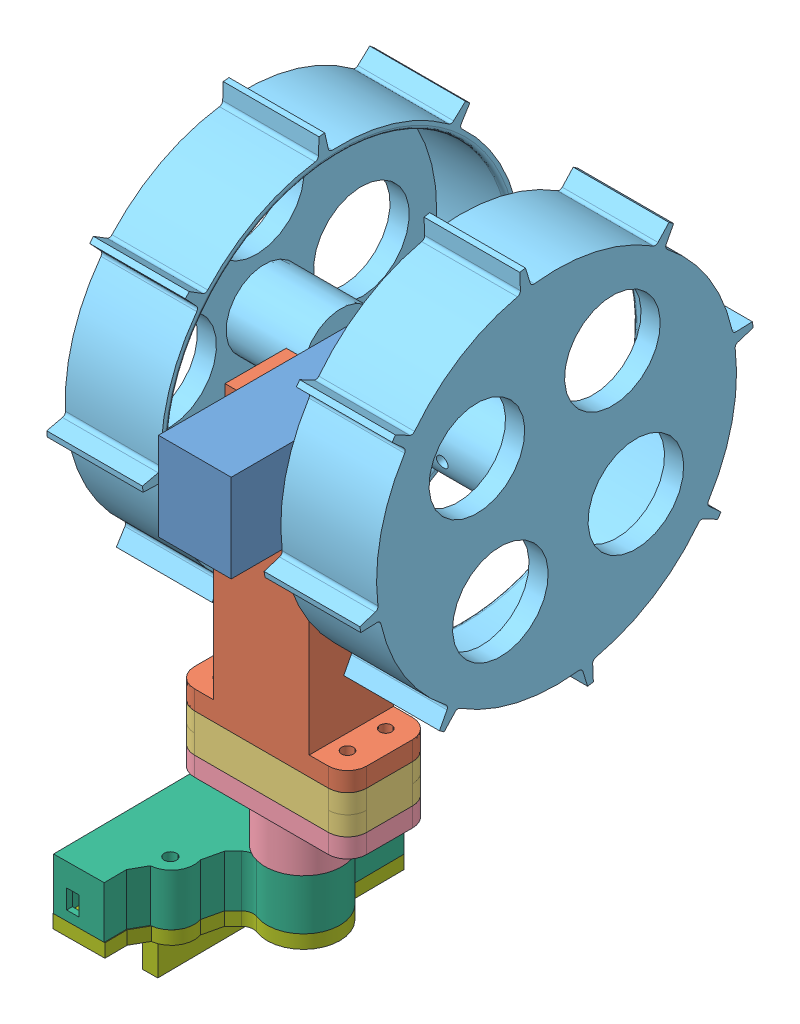
SolidWorks assembly Ensamblaje1, configuration Predeterminado. Lengths in mm.
Overall size (81.29 201.76 146.4).
8 component instances, 7 part files, 16 mates.
Components (placement in the parent):
- motor-1: motor [Predeterminado] at (-10.4339 -8.2966 65) size (39 23 65)
- soporte motor-1: soporte motor [Predeterminado] at (-10.4339 -43.2966 69.1262) x (-1 0 0) z (0 0 1) size (45 75 22)
- separador 2-1: separador 2 [Predeterminado] at (-10.4339 -77.2966 69.1262) size (45 10 22)
- separador v2-1: separador v2 [Predeterminado] at (-10.4339 -87.2966 69.1262) size (45 17 22)
- rueda v2.1-1: rueda v2.1 [Predeterminado] at (30.0214 3.2034 43.5) x (0 -0.985359 -0.170493) z (-1 0 0) size (104 104 25)
- rueda v2.1-2: rueda v2.1 [Predeterminado] at (-51.2707 3.2034 43.5) x (0 -0.771721 0.635961) z (1 0 0) size (104 104 25)
- base 1.b-1: base 1.b [SimetríaPredeterminado] at (-27.9332 -87.2966 69.2777) x (-0.008654 0 -0.999963) z (-0.999963 0 0.008654) size (63.25 13.5 40.3)
- tapa1.a-1: tapa1.a [SimetríaPredeterminado] at (-27.9332 -87.2966 69.2777) x (-0.008654 0 -0.999963) z (-0.999963 0 0.008654) size (63.34 24.56 40.5)
Mates (geometry in assembly coordinates):
- Coincidente1: coincident anti-aligned: plane of motor-1 through (-19.9339 14.7034 32.5) normal (-1 0 0); plane of soporte motor-1 through (-19.9339 -55.2966 77.1262) normal (1 0 0)
- Coincidente3: coincident anti-aligned: plane of motor-1 through (-10.4339 -8.2966 65) normal (0 -1 0); plane of soporte motor-1 through (-0.9339 -8.2966 10.1262) normal (0 1 0)
- Concéntrica2: concentric anti-aligned: cylinder of soporte motor-1 through (6.0661 -100.2966 64.1262) axis (0 1 0) radius 1.55; cylinder of separador 2-1 through (6.0661 -20.2966 64.1262) axis (0 -1 0) radius 1.55
- Coincidente4: coincident aligned: cylinder of separador 2-1 through (6.0661 -20.2966 64.1262) axis (0 -1 0) radius 1.55; circle of separador v2-1
- Concéntrica3: concentric aligned: cylinder of separador 2-1 through (6.0661 -20.2966 64.1262) axis (0 -1 0) radius 1.55; cylinder of separador v2-1 through (6.0661 -30.2966 64.1262) axis (0 -1 0) radius 1.55
- Coincidente5: coincident anti-aligned: plane of separador 2-1 through (-10.4339 -70.2966 69.1262) normal (0 -1 0); plane of separador v2-1 through (-10.4339 -70.2966 69.1262) normal (0 1 0)
- Concéntrica4: concentric anti-aligned: cylinder of motor-1 through (9.0661 3.2034 43.5) axis (-1 0 0) radius 3; cylinder of rueda v2.1-1 through (5.0214 3.2034 43.5) axis (1 0 0) radius 47
- Concéntrica5: concentric anti-aligned: cylinder of motor-1 through (-29.9339 3.2034 43.5) axis (1 0 0) radius 3; cylinder of rueda v2.1-2 through (-26.2707 3.2034 43.5) axis (-1 0 0) radius 10
- Concéntrica6: concentric aligned: cylinder of separador v2-1 through (-10.4339 -42.2966 69.1262) axis (0 -1 0) radius 4.1; cylinder of base 1.b-1 through (-10.4339 -85.7966 69.1262) axis (0 -1 0) radius 3.1
- Concéntrica7: concentric anti-aligned: cylinder of soporte motor-1 through (-26.9339 -100.2966 64.1262) axis (0 1 0) radius 1.55; cylinder of separador v2-1 through (-26.9339 -30.2966 64.1262) axis (0 -1 0) radius 1.55
- Coincidente10: coincident anti-aligned: plane of separador v2-1 through (-10.4339 -87.2966 69.1262) normal (0 -1 0); plane of base 1.b-1 through (4.8685 -87.2966 103.9951) normal (0 1 0)
- Coincidente11: coincident anti-aligned: plane of base 1.b-1 through (-10.4339 -100.7966 69.1262) normal (0 -1 0); plane of tapa1.a-1 through (-26.1237 -100.7966 87.9432) normal (0 1 0)
- Concéntrica8: concentric aligned: cylinder of base 1.b-1 through (-10.4339 -85.7966 69.1262) axis (0 -1 0) radius 3.1; cylinder of tapa1.a-1 through (-10.4339 -99.2966 69.1262) axis (0 -1 0) radius 3.1
- Coincidente12: coincident anti-aligned: plane of soporte motor-1 through (-10.4339 -60.2966 69.1262) normal (0 -1 0); plane of separador 2-1 through (-10.4339 -60.2966 69.1262) normal (0 1 0)
- Paralelo6: parallel aligned: cylinder of base 1.b-1 through (-25.441 -87.2966 45.2552) axis (0 -1 0) radius 1.6; cylinder of tapa1.a-1 through (-25.641 -87.2966 45.2569) axis (0 -1 0) radius 1.6
- Paralelo10: parallel aligned: plane of base 1.b-1 through (-40.9342 -100.7966 103.8783) normal (-0.999963 0 0.008654); plane of tapa1.a-1 through (-41.6088 -104.2966 49.0457) normal (-0.999963 0 0.008654)
